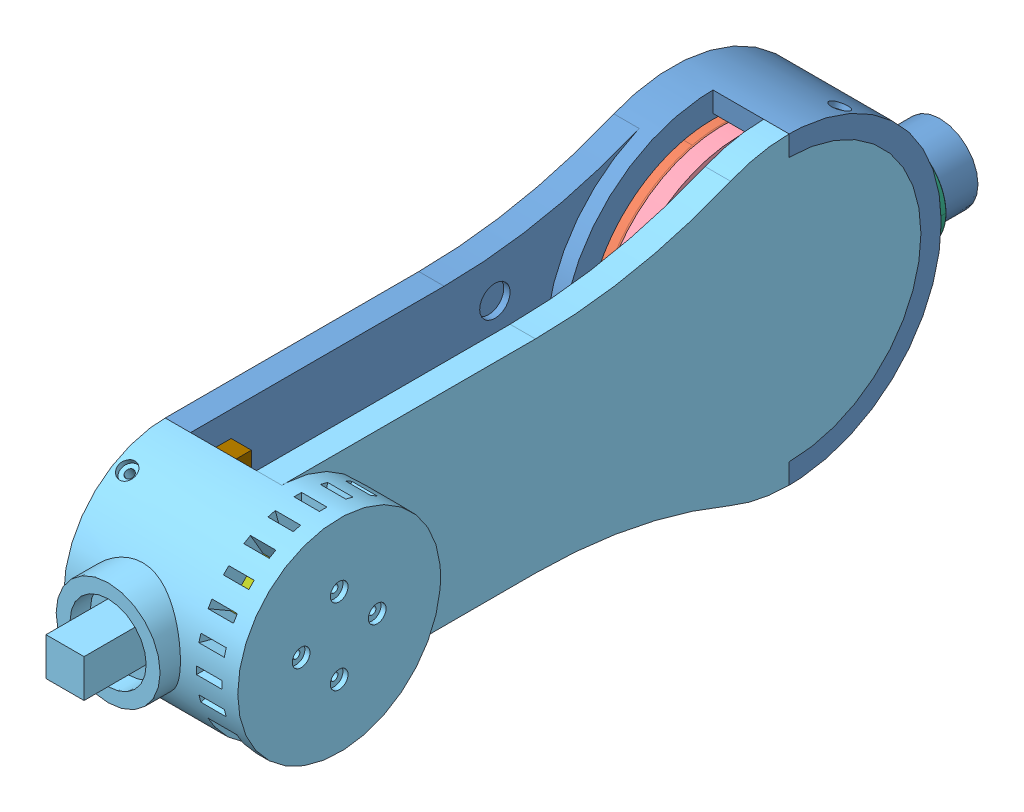
SolidWorks assembly shoulder assembly, configuration Default. Lengths in mm.
Overall size (72.6 149.94 345).
12 component instances, 11 part files, 26 mates.
Components (placement in the parent):
- body hip-1: body hip [Default] at (46.3831 172.9322 161.1274) size (46 120 310)
- W_61816_2Z-1: W_61816_2Z [Default] at (56.3831 172.9322 161.1274) x (1 0 0) z (0 0.97284 0.231481) size (10 124.5 124.5)
- AXK_80105___AS_80105___AS_80105-1: AXK_80105___AS_80105___AS_80105 [Default] at (45.3831 172.9322 161.1274) x (1 0 0) z (0 0.184287 0.982873) size (6 105 105)
- shoulder GT2 120-1: shoulder GT2 120 [Default] at (69.1831 172.9322 161.1274) x (0 -0.773369 0.633957) z (0 0.633957 0.773369) size (86 20 86)
- body hip cover-2: body hip cover [Default] at (82.3831 172.9322 161.1274) size (68.6 120 317)
- W_61706_2RZ-1: W_61706_2RZ [Default] at (71.8831 172.9322 101.1274) x (0 0 -1) z (1 0 0) size (4 46.12 46.12)
- W_61706_2RZ-2: W_61706_2RZ [Default] at (82.3831 172.9322 161.1274) size (4 46.12 46.12)
- MAD5008IPE-1: MAD5008IPE [Default] at (109.9831 172.9322 361.1274) x (0 1 0) z (0 0 1) size (56 29.3 56)
- GT2 15 Teeth motor-1: GT2 15 Teeth motor [Default] at (82.5677 172.9322 361.1274) x (0 1 0) z (0 0 1) size (24 30 24)
- hip joint encoder holder-1: hip joint encoder holder [Default] at (70.3831 172.9322 361.1274) x (0 -1 0) z (0 0 -1) size (80 8 46)
- encoder-1: encoder [Default] at (62.6131 172.9322 361.1274) x (0 -0.992557 0.121778) z (-1 0 0) size (28.79 43.54 9.21)
- W_617_8-1: W_617_8 [Default] at (53.8831 172.9322 361.1274) x (1 0 0) z (0 -0.003591 0.999994) size (2.5 14.75 14.75)
Mates (geometry in assembly coordinates):
- Concentric1: concentric: cylinder of W_61816_2Z-1 through (106.3831 172.9322 161.1274) axis (1 0 0) radius 40; cylinder of body hip-1 through (183.6623 172.9322 161.1274) axis (-1 0 0) radius 42.5
- Coincident1: coincident: plane of body hip-1 through (56.3831 172.9322 161.1274) normal (1 0 0); plane of W_61816_2Z-1 through (56.3831 184.3674 113.0691) normal (-1 0 0)
- Concentric3: concentric: cylinder of body hip-1 through (183.6623 172.9322 161.1274) axis (-1 0 0) radius 42.5; cylinder of AXK_80105___AS_80105___AS_80105-1 through (46.9831 172.9322 161.1274) axis (-1 0 0) radius 40
- Coincident3: coincident: plane of body hip-1 through (48.3831 172.9322 161.1274) normal (-1 0 0); plane of AXK_80105___AS_80105___AS_80105-1 through (48.3831 212.2471 153.7559) normal (1 0 0)
- Concentric8: concentric: cylinder of body hip-1 through (71.8831 172.9322 81.1274) axis (0 0 1) radius 15; cylinder of W_61706_2RZ-1 through (71.8831 172.9322 51.1274) axis (0 0 -1) radius 15
- Coincident8: coincident: plane of body hip-1 through (71.8831 172.9322 101.1274) normal (0 0 -1); plane of W_61706_2RZ-1 through (71.8831 189.0656 101.1274) normal (0 0 1)
- Coincident9: coincident: plane of body hip cover-2 through (86.3831 172.9322 161.1274) normal (-1 0 0); plane of W_61706_2RZ-2 through (86.3831 188.1322 161.1274) normal (1 0 0)
- Concentric10: concentric: cylinder of body hip cover-2 through (86.3831 172.9322 161.1274) axis (-1 0 0) radius 18.5; cylinder of W_61706_2RZ-2 through (132.3831 172.9322 161.1274) axis (1 0 0) radius 18.5
- Coincident10: coincident: plane of body hip cover-2 through (109.9831 172.9322 361.1274) normal (-1 0 0); plane of MAD5008IPE-1 through (109.9831 172.9322 361.1274) normal (1 0 0)
- Concentric11: concentric: cylinder of body hip cover-2 through (82.3831 172.9322 361.1274) axis (1 0 0) radius 30; cylinder of MAD5008IPE-1 through (84.1831 172.9322 361.1274) axis (1 0 0) radius 28
- Coincident11: coincident: plane of body hip-1 through (92.3831 172.9322 161.1274) normal (1 0 0); plane of body hip cover-2 through (92.3831 172.9322 161.1274) normal (1 0 0)
- Concentric13: concentric: cylinder of body hip cover-2 through (82.3831 172.9322 361.1274) axis (1 0 0) radius 30; cylinder of GT2 15 Teeth motor-1 through (82.5677 172.9322 361.1274) axis (1 0 0) radius 12
- Concentric14: concentric: cylinder of MAD5008IPE-1 through (87.1831 165.4322 361.1274) axis (-1 0 0) radius 1.5; cylinder of GT2 15 Teeth motor-1 through (84.1831 165.4322 361.1274) axis (-1 0 0) radius 1.5
- Coincident13: coincident: circle of MAD5008IPE-1; cylinder of GT2 15 Teeth motor-1 through (84.1831 180.4322 361.1274) axis (-1 0 0) radius 1.5
- Coincident14: coincident: plane of MAD5008IPE-1 through (84.1831 172.9322 361.1274) normal (-1 0 0); plane of GT2 15 Teeth motor-1 through (84.1831 160.9322 361.1274) normal (1 0 0)
- Coincident15: coincident: plane of W_61816_2Z-1 through (66.3831 182.3303 121.6301) normal (1 0 0); plane of shoulder GT2 120-1 through (66.3831 172.9322 161.1274) normal (-1 0 0)
- Concentric15: concentric: cylinder of W_61816_2Z-1 through (106.3831 172.9322 161.1274) axis (1 0 0) radius 40; cylinder of shoulder GT2 120-1 through (70.1831 172.9322 161.1274) axis (1 0 0) radius 43
- Concentric18: concentric: cylinder of body hip-1 through (92.3831 172.9322 161.1274) axis (-1 0 0) radius 52; cylinder of body hip cover-2 through (114.9831 172.9322 161.1274) axis (-1 0 0) radius 52
- Concentric19: concentric: cylinder of body hip-1 through (46.3831 172.9322 361.1274) axis (1 0 0) radius 30; cylinder of body hip cover-2 through (82.3831 172.9322 361.1274) axis (1 0 0) radius 30
- Concentric21: concentric: cylinder of GT2 15 Teeth motor-1 through (82.4968 172.9322 361.1274) axis (-1 0 0) radius 4; cylinder of encoder-1 through (66.3831 172.9322 361.1274) axis (-1 0 0) radius 6.3
- Concentric22: concentric: cylinder of GT2 15 Teeth motor-1 through (82.4968 172.9322 361.1274) axis (-1 0 0) radius 4; cylinder of W_617_8-1 through (103.8831 172.9322 361.1274) axis (1 0 0) radius 4
- Coincident18: coincident: plane of body hip-1 through (53.8831 172.9322 361.1274) normal (1 0 0); plane of W_617_8-1 through (53.8831 177.4272 361.1435) normal (-1 0 0)
- Concentric23: concentric: cylinder of GT2 15 Teeth motor-1 through (82.4968 172.9322 361.1274) axis (-1 0 0) radius 4; cylinder of hip joint encoder holder-1 through (66.3831 172.9322 361.1274) axis (1 0 0) radius 4.5
- Coincident19: coincident: plane of body hip cover-2 through (51.3831 142.9322 361.1274) normal (0 0 -1); plane of hip joint encoder holder-1 through (74.3831 156.9322 361.1274) normal (0 0 1)
- Coincident20: coincident: plane of hip joint encoder holder-1 through (66.3831 172.9322 361.1274) normal (-1 0 0); plane of encoder-1 through (66.3831 183.7969 331.5368) normal (1 0 0)
- Concentric24: concentric: cylinder of body hip cover-2 through (70.3831 137.9322 361.1274) axis (0 0 -1) radius 2.05; cylinder of hip joint encoder holder-1 through (70.3831 137.9322 355.1274) axis (0 0 -1) radius 1.7
